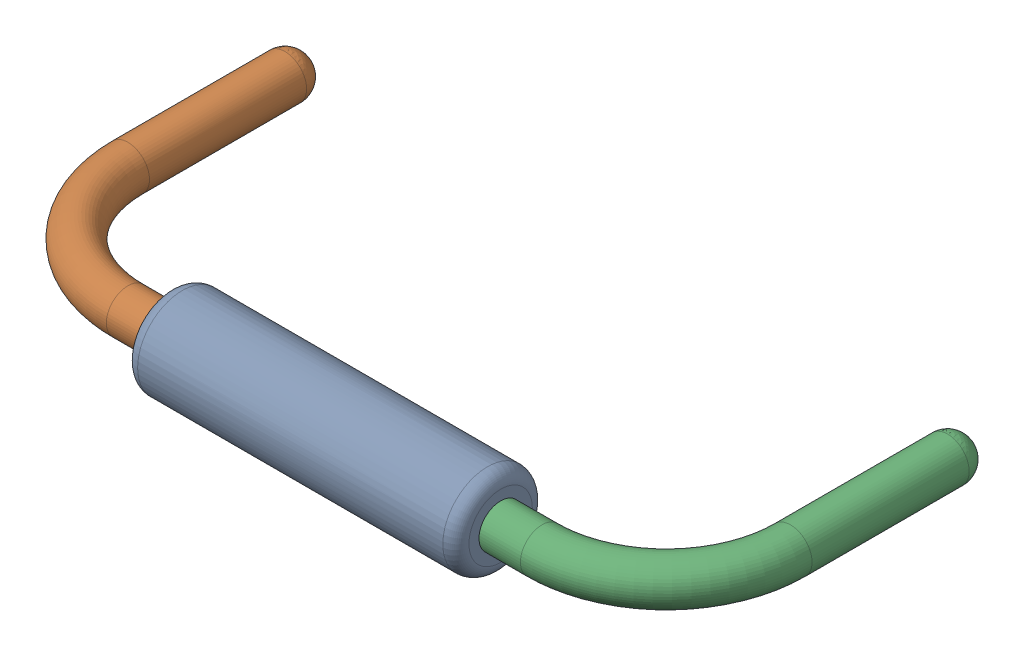
SolidWorks assembly R7, configuration Défaut. Lengths in mm.
Overall size (10.82 1.37 5.33).
4 component instances, 3 part files, 0 mates.
Components (placement in the parent):
- Open CASCADE STEP translator 6.8 1.10.1-1: Open CASCADE STEP translator 6.8 1.10.1 [Défaut] at origin size (10.82 1.37 5.33)
  - Body_1_7-1: Body_1_7 [Défaut] at origin size (5.08 1.37 1.37)
  - Pin_1_4-1: Pin_1_4 [Défaut] at origin size (3.2 0.66 4.98)
  - Pin_2_4-1: Pin_2_4 [Défaut] at (20.32 0 0) x (-1 0 0) z (0 0 1) size (3.2 0.66 4.98)
